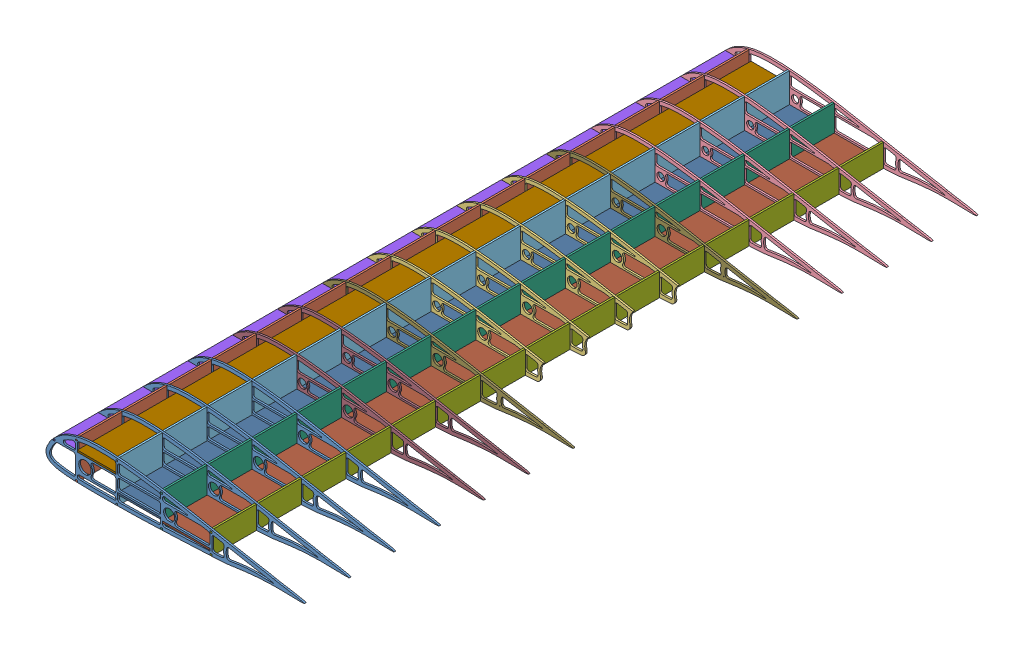
SolidWorks assembly asamblare, configuration Default. Lengths in mm.
Overall size (612.81 165.28 1562.19).
24 component instances, 13 part files, 71 mates.
Components (placement in the parent):
- P-III-2 (15,5%) v6.5_1-2: P-III-2 (15,5%) v6.5_1 [Default] at (-1928.8161 937.7304 -497.3445) size (577.08 93.94 4.01)
- P-III-2 (15,5%) v6.5_1-6: P-III-2 (15,5%) v6.5_1 [Default] at (-1928.8161 937.7304 -697.3445) size (577.08 93.94 4.01)
- vertical aripa sustinere-2: vertical aripa sustinere [Default] at (-1866.8161 973.8493 -1249.3445) x (0 0 1) z (-1 0 0) size (1504 86.8 4)
- P-III-2 (15,5%) v6.5_1-7: P-III-2 (15,5%) v6.5_1 [Default] at (-1928.8161 937.7304 -797.3445) size (577.08 93.94 4.01)
- P-III-2 (15,5%) v6.5_3_fara_eleron-14: P-III-2 (15,5%) v6.5_3_fara_eleron [Default] at (-1928.8161 937.7304 -1197.3445) size (410.66 93.94 62.19)
- P-III-2 (15,5%) v6.5_3_fara_eleron-15: P-III-2 (15,5%) v6.5_3_fara_eleron [Default] at (-1928.8161 937.7304 -1297.3445) size (410.66 93.94 62.19)
- P-III-2 (15,5%) v6.5_3_fara_eleron-16: P-III-2 (15,5%) v6.5_3_fara_eleron [Default] at (-1928.8161 937.7304 -1397.3445) size (410.66 93.94 62.19)
- P-III-2 (15,5%) v6.5_3_fara_eleron-17: P-III-2 (15,5%) v6.5_3_fara_eleron [Default] at (-1928.8161 937.7304 -1497.3445) size (410.66 93.94 62.19)
- P-III-2 (15,5%) v6.5_2-5: P-III-2 (15,5%) v6.5_2 [Default] at (-1928.8161 937.7304 -1697.3445) size (612.81 165.28 62.19)
- P-III-2 (15,5%) v6.5_2-6: P-III-2 (15,5%) v6.5_2 [Default] at (-1928.8161 937.7304 -1797.3445) size (612.81 165.28 62.19)
- P-III-2 (15,5%) v6.5_2-7: P-III-2 (15,5%) v6.5_2 [Default] at (-1928.8161 937.7304 -1897.3445) size (612.81 165.28 62.19)
- P-III-2 (15,5%) v6.5_2-8: P-III-2 (15,5%) v6.5_2 [Default] at (-1928.8161 937.7304 -1997.3445) size (612.81 165.28 62.19)
- vertical aripa sustinere 2-1: vertical aripa sustinere 2 [Default] at (-1780.8161 975.9699 -1249.3445) x (0 0 -1) z (1 0 0) size (1504 91.78 4)
- vertical aripa sustinere 3-1: vertical aripa sustinere 3 [Default] at (-1676.8161 965.6699 -1234.3978) x (0 0 1) z (-1 0 0) size (1504 76.52 4)
- vertical aripa sustinere 4-1: vertical aripa sustinere 4 [Default] at (-1566.6719 865.4795 -1456.7045) x (0 0 1) z (-1 0 0) size (1504 50.94 4)
- orizontal aripa sustinere 1-1: orizontal aripa sustinere 1 [Default] at (-1907.1183 989.1036 -1249.3445) x (1 0 0) z (0 -1 0) size (49.38 1504 4) (hidden)
- P-III-2 (15,5%) v6.5_1-8: P-III-2 (15,5%) v6.5_1 [Default] at (-1928.8161 937.7304 -597.3445) size (577.08 93.94 4.01)
- orizontal aripa sustinere 2-1: orizontal aripa sustinere 2 [Default] at (-1823.8161 993.1106 -1249.3445) x (1 0 0) z (0 -1 0) size (86 1504 4) (hidden)
- orizontal aripa sustinere 3-1: orizontal aripa sustinere 3 [Default] at (-1717.5635 956.1106 -1912.8052) x (1 0 0) z (0 -1 0) size (96 1504 4) (hidden)
- orizontal aripa sustinere 4-1: orizontal aripa sustinere 4 [Default] at (-944.1975 947.1106 -1135.3428) x (0 0 -1) z (0 1 0) size (1504 106.14 4) (hidden)
- P-III-2 (15,5%) v6.5_3_eleron-19: P-III-2 (15,5%) v6.5_3_eleron [Default] at (-1928.8161 937.7304 -1597.3445) size (577.08 93.94 62.19)
- P-III-2 (15,5%) v6.5_3_eleron-21: P-III-2 (15,5%) v6.5_3_eleron [Default] at (-1928.8161 937.7304 -1097.3445) size (577.08 93.94 62.19)
- P-III-2 (15,5%) v6.5_3-19: P-III-2 (15,5%) v6.5_3 [Default] at (-1928.8161 937.7304 -997.3445) size (577.08 93.94 62.19)
- P-III-2 (15,5%) v6.5_3-20: P-III-2 (15,5%) v6.5_3 [Default] at (-1928.8161 937.7304 -897.3445) size (577.08 93.94 62.19)
Mates (geometry in assembly coordinates):
- Parallel14: parallel anti-aligned: plane of P-III-2 (15,5%) v6.5_1-2 through (-1928.8161 1010.1473 -501.3445) normal (0 1 0); plane of vertical aripa sustinere-2 through (-1870.8161 1010.1473 -1249.3445) normal (0 -1 0)
- Coincident78: coincident anti-aligned: line of P-III-2 (15,5%) v6.5_1-2 through (-1866.8161 1012.8403 -497.3445) axis (-1 0 0); line of vertical aripa sustinere-2 through (-1870.8161 1012.8403 -497.3445) axis (1 0 0)
- Coincident79: coincident anti-aligned: line of P-III-2 (15,5%) v6.5_1-2 through (-1866.8161 1010.1473 -497.3445) axis (0 1 0); line of vertical aripa sustinere-2 through (-1866.8161 1012.8403 -497.3445) axis (0 -1 0)
- Coincident84: coincident anti-aligned: plane of P-III-2 (15,5%) v6.5_1-6 through (-1928.8161 937.7304 -697.3445) normal (0 0 1); plane of vertical aripa sustinere-2 through (-1870.8161 973.8493 -697.3445) normal (0 0 -1)
- Parallel15: parallel anti-aligned: line of vertical aripa sustinere-2 through (-1870.8161 1012.8403 -701.3445) axis (1 0 0); line of P-III-2 (15,5%) v6.5_1-6 through (-1866.8161 1012.8403 -701.3445) axis (-1 0 0)
- Coincident87: coincident anti-aligned: plane of P-III-2 (15,5%) v6.5_1-6 through (-1870.8161 937.7304 -701.3445) normal (1 0 0); plane of vertical aripa sustinere-2 through (-1870.8161 973.8493 -1249.3445) normal (-1 0 0)
- Coincident88: coincident anti-aligned: line of P-III-2 (15,5%) v6.5_1-6 through (-1866.8161 1012.8403 -701.3445) axis (-1 0 0); line of vertical aripa sustinere-2 through (-1870.8161 1012.8403 -701.3445) axis (1 0 0)
- Coincident89: coincident anti-aligned: plane of vertical aripa sustinere-2 through (-1870.8161 973.8493 -797.3445) normal (0 0 -1); plane of P-III-2 (15,5%) v6.5_1-7 through (-1928.8161 937.7304 -797.3445) normal (0 0 1)
- Coincident90: coincident anti-aligned: plane of vertical aripa sustinere-2 through (-1870.8161 1012.8403 -1249.3445) normal (0 1 0); plane of P-III-2 (15,5%) v6.5_1-7 through (-1928.8161 1012.8403 -801.3445) normal (0 -1 0)
- Coincident91: coincident anti-aligned: plane of vertical aripa sustinere-2 through (-1870.8161 973.8493 -1249.3445) normal (-1 0 0); plane of P-III-2 (15,5%) v6.5_1-7 through (-1870.8161 937.7304 -801.3445) normal (1 0 0)
- Coincident103: coincident anti-aligned: plane of vertical aripa sustinere-2 through (-1870.8161 1012.8403 -1249.3445) normal (0 1 0); plane of P-III-2 (15,5%) v6.5_3_fara_eleron-14 through (-1928.8161 1012.8403 -1201.3445) normal (0 -1 0)
- Coincident105: coincident anti-aligned: plane of vertical aripa sustinere-2 through (-1866.8161 973.8493 -1249.3445) normal (1 0 0); plane of P-III-2 (15,5%) v6.5_3_fara_eleron-14 through (-1866.8161 937.7304 -1201.3445) normal (-1 0 0)
- Coincident107: coincident anti-aligned: plane of vertical aripa sustinere-2 through (-1870.8161 973.8493 -1197.3445) normal (0 0 -1); plane of P-III-2 (15,5%) v6.5_3_fara_eleron-14 through (-1928.8161 937.7304 -1197.3445) normal (0 0 1)
- Coincident108: coincident anti-aligned: plane of vertical aripa sustinere-2 through (-1870.8161 973.8493 -1301.3445) normal (0 0 1); plane of P-III-2 (15,5%) v6.5_3_fara_eleron-15 through (-1928.8161 937.7304 -1301.3445) normal (0 0 -1)
- Coincident109: coincident anti-aligned: plane of vertical aripa sustinere-2 through (-1870.8161 973.8493 -1401.3445) normal (0 0 1); plane of P-III-2 (15,5%) v6.5_3_fara_eleron-16 through (-1928.8161 937.7304 -1401.3445) normal (0 0 -1)
- Coincident110: coincident anti-aligned: plane of vertical aripa sustinere-2 through (-1870.8161 973.8493 -1497.3445) normal (0 0 -1); plane of P-III-2 (15,5%) v6.5_3_fara_eleron-17 through (-1928.8161 937.7304 -1497.3445) normal (0 0 1)
- Coincident112: coincident anti-aligned: plane of vertical aripa sustinere-2 through (-1870.8161 973.8493 -1697.3445) normal (0 0 -1); plane of P-III-2 (15,5%) v6.5_2-5 through (-1928.8161 937.7304 -1697.3445) normal (0 0 1)
- Coincident113: coincident anti-aligned: plane of vertical aripa sustinere-2 through (-1870.8161 973.8493 -1797.3445) normal (0 0 -1); plane of P-III-2 (15,5%) v6.5_2-6 through (-1928.8161 937.7304 -1797.3445) normal (0 0 1)
- Coincident114: coincident anti-aligned: plane of vertical aripa sustinere-2 through (-1870.8161 973.8493 -1897.3445) normal (0 0 -1); plane of P-III-2 (15,5%) v6.5_2-7 through (-1928.8161 937.7304 -1897.3445) normal (0 0 1)
- Coincident115: coincident anti-aligned: plane of vertical aripa sustinere-2 through (-1870.8161 973.8493 -1997.3445) normal (0 0 -1); plane of P-III-2 (15,5%) v6.5_2-8 through (-1928.8161 937.7304 -1997.3445) normal (0 0 1)
- Coincident116: coincident anti-aligned: plane of vertical aripa sustinere-2 through (-1870.8161 1010.1473 -1249.3445) normal (0 -1 0); plane of P-III-2 (15,5%) v6.5_3_fara_eleron-15 through (-1928.8161 1010.1473 -1301.3445) normal (0 1 0)
- Coincident117: coincident anti-aligned: plane of vertical aripa sustinere-2 through (-1870.8161 1010.1473 -1249.3445) normal (0 -1 0); plane of P-III-2 (15,5%) v6.5_3_fara_eleron-16 through (-1928.8161 1010.1473 -1401.3445) normal (0 1 0)
- Coincident118: coincident anti-aligned: plane of vertical aripa sustinere-2 through (-1870.8161 1012.8403 -1249.3445) normal (0 1 0); plane of P-III-2 (15,5%) v6.5_3_fara_eleron-17 through (-1928.8161 1012.8403 -1501.3445) normal (0 -1 0)
- Coincident120: coincident anti-aligned: plane of vertical aripa sustinere-2 through (-1870.8161 1010.1473 -1249.3445) normal (0 -1 0); plane of P-III-2 (15,5%) v6.5_2-5 through (-1928.8161 1010.1473 -1701.3445) normal (0 1 0)
- Coincident121: coincident anti-aligned: plane of vertical aripa sustinere-2 through (-1870.8161 1010.1473 -1249.3445) normal (0 -1 0); plane of P-III-2 (15,5%) v6.5_2-6 through (-1928.8161 1010.1473 -1801.3445) normal (0 1 0)
- Coincident122: coincident anti-aligned: plane of vertical aripa sustinere-2 through (-1870.8161 1010.1473 -1249.3445) normal (0 -1 0); plane of P-III-2 (15,5%) v6.5_2-7 through (-1928.8161 1010.1473 -1901.3445) normal (0 1 0)
- Coincident123: coincident anti-aligned: plane of vertical aripa sustinere-2 through (-1870.8161 1010.1473 -1249.3445) normal (0 -1 0); plane of P-III-2 (15,5%) v6.5_2-8 through (-1928.8161 1010.1473 -2001.3445) normal (0 1 0)
- Coincident124: coincident anti-aligned: plane of vertical aripa sustinere-2 through (-1866.8161 973.8493 -1249.3445) normal (1 0 0); plane of P-III-2 (15,5%) v6.5_2-8 through (-1866.8161 937.7304 -2001.3445) normal (-1 0 0)
- Coincident125: coincident anti-aligned: plane of vertical aripa sustinere-2 through (-1866.8161 973.8493 -1249.3445) normal (1 0 0); plane of P-III-2 (15,5%) v6.5_2-7 through (-1866.8161 937.7304 -1901.3445) normal (-1 0 0)
- Coincident126: coincident anti-aligned: plane of vertical aripa sustinere-2 through (-1866.8161 973.8493 -1249.3445) normal (1 0 0); plane of P-III-2 (15,5%) v6.5_2-6 through (-1866.8161 937.7304 -1801.3445) normal (-1 0 0)
- Coincident127: coincident anti-aligned: plane of vertical aripa sustinere-2 through (-1866.8161 973.8493 -1249.3445) normal (1 0 0); plane of P-III-2 (15,5%) v6.5_2-5 through (-1866.8161 937.7304 -1701.3445) normal (-1 0 0)
- Coincident129: coincident anti-aligned: plane of vertical aripa sustinere-2 through (-1866.8161 973.8493 -1249.3445) normal (1 0 0); plane of P-III-2 (15,5%) v6.5_3_fara_eleron-17 through (-1866.8161 937.7304 -1501.3445) normal (-1 0 0)
- Coincident130: coincident anti-aligned: plane of vertical aripa sustinere-2 through (-1866.8161 973.8493 -1249.3445) normal (1 0 0); plane of P-III-2 (15,5%) v6.5_3_fara_eleron-16 through (-1866.8161 937.7304 -1401.3445) normal (-1 0 0)
- Coincident131: coincident anti-aligned: plane of vertical aripa sustinere-2 through (-1866.8161 973.8493 -1249.3445) normal (1 0 0); plane of P-III-2 (15,5%) v6.5_3_fara_eleron-15 through (-1866.8161 937.7304 -1301.3445) normal (-1 0 0)
- Parallel17: parallel anti-aligned: plane of P-III-2 (15,5%) v6.5_2-8 through (-1928.8161 985.1036 -2001.3445) normal (0 -1 0); plane of assembly through (0 0 0) normal (0 1 0)
- Coincident137: coincident anti-aligned: plane of P-III-2 (15,5%) v6.5_2-8 through (-1780.8161 937.7304 -2001.3445) normal (1 0 0); plane of vertical aripa sustinere 2-1 through (-1780.8161 975.9699 -1249.3445) normal (-1 0 0)
- Coincident138: coincident anti-aligned: plane of P-III-2 (15,5%) v6.5_2-8 through (-1928.8161 1018.1045 -2001.3445) normal (0 -1 0); plane of vertical aripa sustinere 2-1 through (-1776.8161 1018.1045 -1249.3445) normal (0 1 0)
- Coincident139: coincident aligned: plane of P-III-2 (15,5%) v6.5_2-8 through (-1928.8161 937.7304 -2001.3445) normal (0 0 -1); plane of vertical aripa sustinere 2-1 through (-1776.8161 975.9699 -2001.3445) normal (0 0 -1)
- Coincident140: coincident anti-aligned: plane of P-III-2 (15,5%) v6.5_2-8 through (-1676.8161 937.7304 -2001.3445) normal (-1 0 0); plane of vertical aripa sustinere 3-1 through (-1676.8161 965.6699 -1234.3978) normal (1 0 0)
- Coincident141: coincident anti-aligned: plane of P-III-2 (15,5%) v6.5_2-8 through (-1928.8161 1005.7142 -2001.3445) normal (0 -1 0); plane of vertical aripa sustinere 3-1 through (-1680.8161 1005.7142 -1234.3978) normal (0 1 0)
- Coincident142: coincident aligned: plane of P-III-2 (15,5%) v6.5_2-8 through (-1928.8161 937.7304 -2001.3445) normal (0 0 -1); plane of vertical aripa sustinere 3-1 through (-1680.8161 965.6699 -2001.3445) normal (0 0 -1)
- Coincident143: coincident anti-aligned: plane of P-III-2 (15,5%) v6.5_2-8 through (-1566.6719 937.7304 -2001.3445) normal (-1 0 0); plane of vertical aripa sustinere 4-1 through (-1566.6719 865.4795 -1456.7045) normal (1 0 0)
- Coincident144: coincident aligned: plane of P-III-2 (15,5%) v6.5_2-8 through (-1928.8161 937.7304 -2001.3445) normal (0 0 -1); plane of vertical aripa sustinere 4-1 through (-1570.6719 865.4795 -2001.3445) normal (0 0 -1)
- Coincident145: coincident anti-aligned: plane of P-III-2 (15,5%) v6.5_2-8 through (-1928.8161 981.446 -2001.3445) normal (0 1 0); plane of vertical aripa sustinere 4-1 through (-1570.6719 981.446 -1456.7045) normal (0 -1 0)
- Coincident146: coincident anti-aligned: plane of P-III-2 (15,5%) v6.5_2-7 through (-1928.8161 989.1036 -1901.3445) normal (0 -1 0); plane of orizontal aripa sustinere 1-1 through (-1907.1183 989.1036 -1249.3445) normal (0 1 0)
- Coincident147: coincident aligned: plane of P-III-2 (15,5%) v6.5_2-8 through (-1928.8161 937.7304 -2001.3445) normal (0 0 -1); plane of orizontal aripa sustinere 1-1 through (-1920.2008 985.1036 -2001.3445) normal (0 0 -1)
- Coincident150: coincident anti-aligned: plane of vertical aripa sustinere-2 through (-1870.8161 973.8493 -1249.3445) normal (-1 0 0); plane of orizontal aripa sustinere 1-1 through (-1870.8161 985.1036 -1901.3445) normal (1 0 0)
- Coincident151: coincident anti-aligned: plane of vertical aripa sustinere-2 through (-1870.8161 973.8493 -597.3445) normal (0 0 -1); plane of P-III-2 (15,5%) v6.5_1-8 through (-1928.8161 937.7304 -597.3445) normal (0 0 1)
- Coincident156: coincident anti-aligned: plane of vertical aripa sustinere-2 through (-1870.8161 1012.8403 -1249.3445) normal (0 1 0); plane of P-III-2 (15,5%) v6.5_1-8 through (-1928.8161 1012.8403 -601.3445) normal (0 -1 0)
- Coincident157: coincident anti-aligned: plane of vertical aripa sustinere-2 through (-1866.8161 973.8493 -1249.3445) normal (1 0 0); plane of P-III-2 (15,5%) v6.5_1-8 through (-1866.8161 937.7304 -601.3445) normal (-1 0 0)
- Coincident161: coincident anti-aligned: plane of P-III-2 (15,5%) v6.5_1-2 through (-1928.8161 989.1106 -501.3445) normal (0 1 0); plane of orizontal aripa sustinere 2-1 through (-1823.8161 989.1106 -1249.3445) normal (0 -1 0)
- Coincident162: coincident anti-aligned: plane of vertical aripa sustinere-2 through (-1866.8161 973.8493 -1249.3445) normal (1 0 0); plane of orizontal aripa sustinere 2-1 through (-1866.8161 989.1106 -497.3445) normal (-1 0 0)
- Coincident163: coincident aligned: plane of P-III-2 (15,5%) v6.5_1-2 through (-1928.8161 937.7304 -497.3445) normal (0 0 1); plane of orizontal aripa sustinere 2-1 through (-1861.8161 989.1106 -497.3445) normal (0 0 1)
- Coincident167: coincident anti-aligned: plane of P-III-2 (15,5%) v6.5_1-2 through (-1928.8161 951.1106 -501.3445) normal (0 -1 0); plane of orizontal aripa sustinere 4-1 through (-944.1975 951.1106 -1135.3428) normal (0 1 0)
- Coincident168: coincident aligned: plane of P-III-2 (15,5%) v6.5_1-2 through (-1928.8161 937.7304 -497.3445) normal (0 0 1); plane of orizontal aripa sustinere 4-1 through (-1676.8161 951.1106 -497.3445) normal (0 0 1)
- Coincident170: coincident anti-aligned: plane of P-III-2 (15,5%) v6.5_1-2 through (-1676.8161 937.7304 -501.3445) normal (1 0 0); plane of orizontal aripa sustinere 4-1 through (-1676.8161 951.1106 -497.3445) normal (-1 0 0)
- Coincident171: coincident anti-aligned: plane of P-III-2 (15,5%) v6.5_1-2 through (-1928.8161 956.1106 -501.3445) normal (0 -1 0); plane of orizontal aripa sustinere 3-1 through (-1717.5635 956.1106 -1912.8052) normal (0 1 0)
- Coincident172: coincident anti-aligned: plane of P-III-2 (15,5%) v6.5_1-2 through (-1680.8161 937.7304 -501.3445) normal (-1 0 0); plane of orizontal aripa sustinere 3-1 through (-1680.8161 952.1106 -497.3445) normal (1 0 0)
- Coincident173: coincident aligned: plane of P-III-2 (15,5%) v6.5_1-2 through (-1928.8161 937.7304 -497.3445) normal (0 0 1); plane of orizontal aripa sustinere 3-1 through (-1776.8161 952.1106 -497.3445) normal (0 0 1)
- Coincident174: coincident aligned: plane of vertical aripa sustinere 4-1 through (-1566.6719 865.4795 -1456.7045) normal (1 0 0); plane of P-III-2 (15,5%) v6.5_3_eleron-19 through (-1566.6719 937.7304 -1601.3445) normal (1 0 0)
- Coincident175: coincident anti-aligned: plane of vertical aripa sustinere 4-1 through (-1570.6719 941.7888 -1456.7045) normal (0 1 0); plane of P-III-2 (15,5%) v6.5_3_eleron-19 through (-1928.8161 941.7888 -1601.3445) normal (0 -1 0)
- Coincident176: coincident anti-aligned: plane of vertical aripa sustinere 4-1 through (-1570.6719 865.4795 -1597.3445) normal (0 0 -1); plane of P-III-2 (15,5%) v6.5_3_eleron-19 through (-1928.8161 937.7304 -1597.3445) normal (0 0 1)
- Coincident180: coincident anti-aligned: plane of vertical aripa sustinere 4-1 through (-1570.6719 865.4795 -1097.3445) normal (0 0 -1); plane of P-III-2 (15,5%) v6.5_3_eleron-21 through (-1928.8161 937.7304 -1097.3445) normal (0 0 1)
- Coincident181: coincident anti-aligned: plane of vertical aripa sustinere 4-1 through (-1570.6719 941.7888 -1456.7045) normal (0 1 0); plane of P-III-2 (15,5%) v6.5_3_eleron-21 through (-1928.8161 941.7888 -1101.3445) normal (0 -1 0)
- Coincident182: coincident aligned: plane of vertical aripa sustinere 4-1 through (-1566.6719 865.4795 -1456.7045) normal (1 0 0); plane of P-III-2 (15,5%) v6.5_3_eleron-21 through (-1566.6719 937.7304 -1101.3445) normal (1 0 0)
- Coincident183: coincident anti-aligned: plane of vertical aripa sustinere 4-1 through (-1570.6719 865.4795 -1456.7045) normal (-1 0 0); plane of P-III-2 (15,5%) v6.5_3-20 through (-1570.6719 937.7304 -901.3445) normal (1 0 0)
- Coincident184: coincident anti-aligned: plane of vertical aripa sustinere 4-1 through (-1570.6719 865.4795 -897.3445) normal (0 0 -1); plane of P-III-2 (15,5%) v6.5_3-20 through (-1928.8161 937.7304 -897.3445) normal (0 0 1)
- Coincident185: coincident anti-aligned: plane of vertical aripa sustinere 4-1 through (-1570.6719 941.7888 -1456.7045) normal (0 1 0); plane of P-III-2 (15,5%) v6.5_3-19 through (-1928.8161 941.7888 -1001.3445) normal (0 -1 0)
- Coincident186: coincident anti-aligned: plane of vertical aripa sustinere 4-1 through (-1570.6719 865.4795 -997.3445) normal (0 0 -1); plane of P-III-2 (15,5%) v6.5_3-19 through (-1928.8161 937.7304 -997.3445) normal (0 0 1)
- Coincident187: coincident aligned: plane of vertical aripa sustinere 4-1 through (-1566.6719 865.4795 -1456.7045) normal (1 0 0); plane of P-III-2 (15,5%) v6.5_3-19 through (-1566.6719 937.7304 -1001.3445) normal (1 0 0)
- Coincident188: coincident anti-aligned: plane of vertical aripa sustinere 3-1 through (-1680.8161 936.7217 -1234.3978) normal (0 1 0); plane of P-III-2 (15,5%) v6.5_3-20 through (-1928.8161 936.7217 -901.3445) normal (0 -1 0)
